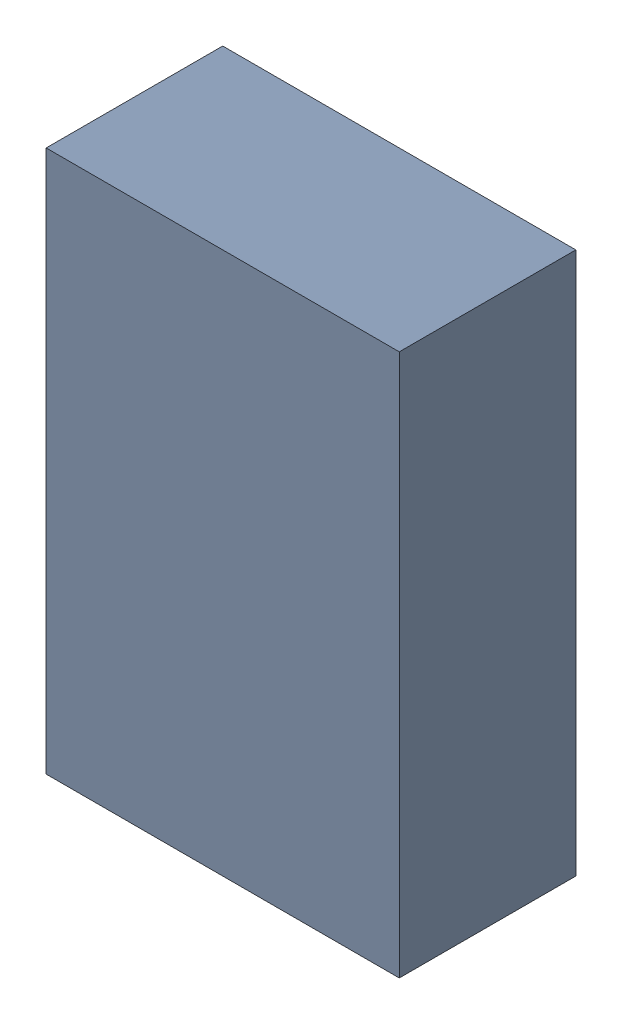
SolidWorks assembly R6, configuration Default. Lengths in mm.
Overall size (1.4 2.15 0.7).
2 component instances, 1 part files, 0 mates.
Components (placement in the parent):
- 959208120-1: 959208120 [Default] at (122.9827 82.385 0) size (1.4 2.15 0.7)
  - Extruded-20-1: Extruded-20 [Default] at origin size (1.4 2.15 0.7)
